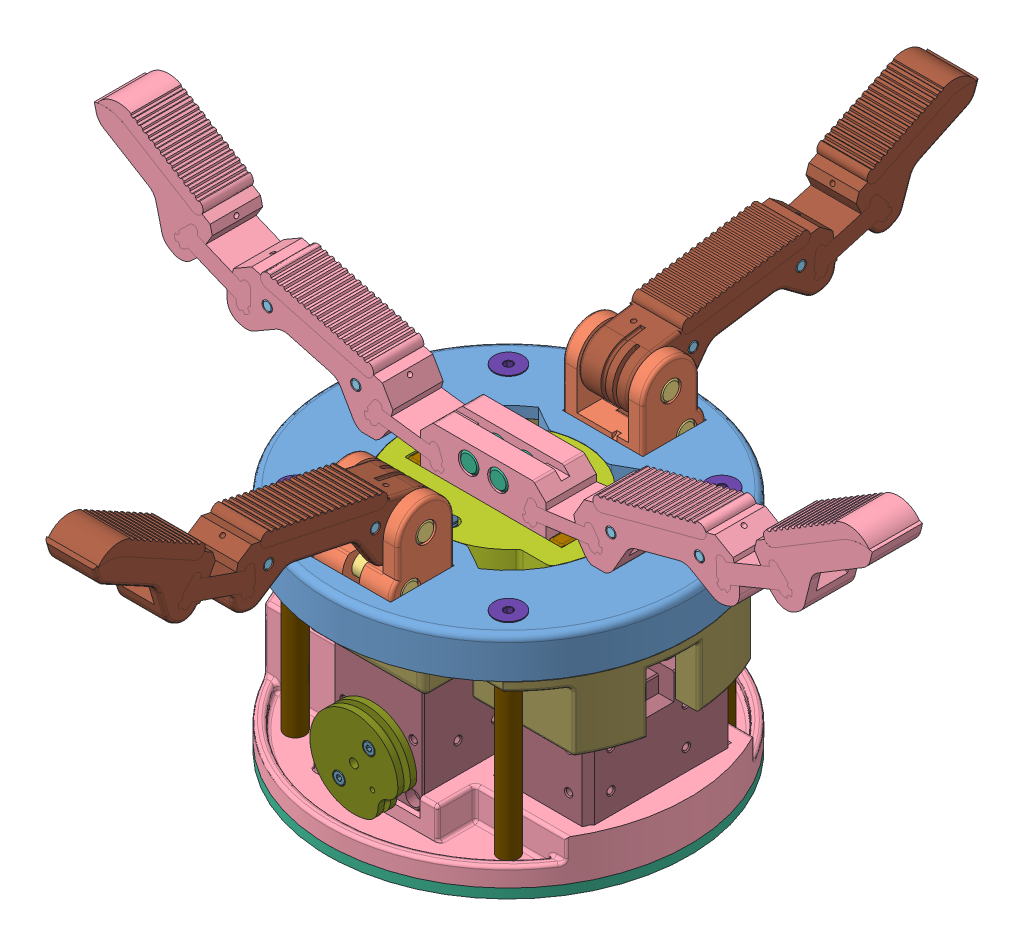
SolidWorks assembly hand_q, configuration Default. Lengths in mm.
Overall size (247.99 129.84 290.7).
63 component instances, 24 part files, 66 mates.
Components (placement in the parent):
- asm_upper_hand-1: asm_upper_hand [Default] at (50.9892 100.6769 120.1073) size (247.99 72.36 290.7)
  - top_outer-1: top_outer [Default] at (34.5547 64.3421 89.7406) size (115 12.78 115)
  - finger_base_pf-1: finger_base_pf [Default] at (4.6376 22.7271 -88.248) size (33.5 28.98 20.18)
    - pivot_base-1: pivot_base [Default] at (29.9046 41.615 134.046) x (-1 0 0) z (0 0 -1) size (33.5 28.98 20.18)
    - 98381A542 D1-4 L1-1: 98381A542 D1-4 L1 [98381A542] at (29.9546 61.59 138.9886) size (25.4 6.35 6.35)
    - 98381A542 D1-4 L1-2: 98381A542 D1-4 L1 [98381A542] at (29.9546 47.8525 134.046) size (25.4 6.35 6.35)
  - finger_base_pf-2: finger_base_pf [Default] at (64.4468 22.7271 267.7291) x (-1 0 0) z (0 0 -1) size (33.5 28.98 20.18)
    - pivot_base-1: pivot_base [Default] at (29.9046 41.615 134.046) x (-1 0 0) z (0 0 -1) size (33.5 28.98 20.18)
    - 98381A542 D1-4 L1-1: 98381A542 D1-4 L1 [98381A542] at (29.9546 61.59 138.9886) size (25.4 6.35 6.35)
    - 98381A542 D1-4 L1-2: 98381A542 D1-4 L1 [98381A542] at (29.9546 47.8525 134.046) size (25.4 6.35 6.35)
  - q_ffff-1: q_ffff [Default] at (44.5547 76.3421 89.7516) x (-0.001108 0 0.999999) z (-0.999999 0 -0.001108) size (24 58.4 247.96)
  - 98381A472 D1-8 L5-8-1: 98381A472 D1-8 L5-8 [98381A472] at (75.1996 82.7614 89.8481) x (-0.001108 0 0.999999) z (-0.999999 0 -0.001108) size (15.88 3.17 3.17)
  - 98381A539 D1-4 L5-8-1: 98381A539 D1-4 L5-8 [98381A539] at (29.8796 79.1671 89.7979) x (-0.001108 0 0.999999) z (-0.999999 0 -0.001108) size (15.88 6.35 6.35)
  - 98381A472 D1-8 L5-8-2: 98381A472 D1-8 L5-8 [98381A472] at (-34.3036 90.3211 89.7268) x (-0.001108 0 0.999999) z (-0.999999 0 -0.001108) size (15.88 3.17 3.17)
  - 98381A472 D1-8 L5-8-3: 98381A472 D1-8 L5-8 [98381A472] at (-6.0903 82.7614 89.758) x (-0.001108 0 0.999999) z (-0.999999 0 -0.001108) size (15.88 3.17 3.17)
  - 98381A472 D1-8 L5-8-4: 98381A472 D1-8 L5-8 [98381A472] at (103.4129 90.3211 89.8793) x (-0.001108 0 0.999999) z (-0.999999 0 -0.001108) size (15.88 3.17 3.17)
  - 98381A539 D1-4 L5-8-2: 98381A539 D1-4 L5-8 [98381A539] at (39.2296 79.1671 89.8082) x (-0.001108 0 0.999999) z (-0.999999 0 -0.001108) size (15.88 6.35 6.35)
  - top_inner-1: top_inner [Default] at (34.5547 64.3421 89.7406) x (0.999999 0 0.001108) z (-0.001108 0 0.999999) size (72 6.4 48)
  - 93365A130 6-32 insert-1: 93365A130 6-32 insert [Default] at (34.5752 68.1521 71.2406) x (1 0 0) z (0 -1 0) size (5.23 5.23 3.81)
  - 93365A130 6-32 insert-2: 93365A130 6-32 insert [Default] at (34.5342 68.1521 108.2406) x (1 0 0) z (0 -1 0) size (5.23 5.23 3.81)
  - gear_main-1: gear_main [Default] at (34.5547 61.0921 89.7406) x (-0.999999 0 -0.001108) z (0 -1 0) size (59.97 59.97 15.65)
  - 92196A146 6-32 L3-8  socket-1: 92196A146 6-32 L3-8  socket [Default] at (34.5342 58.3421 108.2406) x (1 0 0) z (0 1 0) size (5.74 5.74 13.34)
  - 92196A146 6-32 L3-8  socket-3: 92196A146 6-32 L3-8  socket [Default] at (34.5752 58.3421 71.2406) x (1 0 0) z (0 1 0) size (5.74 5.74 13.34)
  - q_pf-1: q_pf [Default] at (34.6922 84.3171 50.7406) x (1 0 0) z (0 -0.14871 0.988881) size (16.19 30.86 115.48)
  - 98381A472 D1-8 L5-8-5: 98381A472 D1-8 L5-8 [98381A472] at (34.7547 88.2661 39.0225) size (15.88 3.17 3.17)
  - 98381A472 D1-8 L5-8-6: 98381A472 D1-8 L5-8 [98381A472] at (34.7547 93.4305 4.6806) size (15.88 3.17 3.17)
  - 98381A472 D1-8 L5-8-7: 98381A472 D1-8 L5-8 [98381A472] at (34.6297 96.0106 174.214) x (-1 0 0) z (0 0 -1) size (15.88 3.17 3.17)
  - q_pf-2: q_pf [Default] at (34.6922 84.3171 128.7406) x (-1 0 0) z (0 -0.204177 -0.978934) size (16.19 30.86 115.48)
  - 98381A472 D1-8 L5-8-8: 98381A472 D1-8 L5-8 [98381A472] at (34.6297 88.9199 140.2176) x (-1 0 0) z (0 0 -1) size (15.88 3.17 3.17)
- mid_clamp-1: mid_clamp [Default] at (85.5439 155.519 209.8478) size (115 28.59 91.05)
- dynamixel XM-430-1: dynamixel XM-430 [Default] at (47.6198 138.519 196.7478) x (1 0 0) z (0 1 0) size (28.5 46.5 37.88)
- 91290A012 M2 L5 socket-1: 91290A012 M2 L5 socket [91290A012] at (53.2767 156.3984 202.4047) x (1 0 0) z (0 -1 0) size (3.8 3.8 7.09)
- gear_motor-1: gear_motor [Default] at (46.9298 161.9484 197.5346) x (1 0 0) z (0 1 0) size (27.89 27.89 7.3)
- dynamixel XM-430-2: dynamixel XM-430 [Default] at (85.7439 120.269 234.3728) x (-1 0 0) z (0 0 1) size (28.5 46.5 37.88)
- dynamixel XM-430-3: dynamixel XM-430 [Default] at (85.7439 120.269 185.3228) x (1 0 0) z (0 0 -1) size (28.5 46.5 37.88)
- dynamixel XM-430-4: dynamixel XM-430 [Default] at (121.2351 127.519 199.1567) x (-1 0 0) z (0 -1 0) size (28.5 46.5 37.88)
- horn2-1: horn2 [Default] at (85.7439 120.269 256.2522) x (0.804523 -0.593922 0) z (0 0 1) size (26.25 28 6)
- horn2-2: horn2 [Default] at (85.7439 120.269 163.4435) x (-0.894152 -0.447763 0) z (0 0 -1) size (26.25 28 6)
- 91290A012 M2 L5 socket-2: 91290A012 M2 L5 socket [91290A012] at (90.4953 126.7052 252.2522) x (-1 0 0) z (0 0 -1) size (3.8 3.8 7.09)
- 91290A012 M2 L5 socket-3: 91290A012 M2 L5 socket [91290A012] at (80.9926 113.8328 252.2522) x (-1 0 0) z (0 0 -1) size (3.8 3.8 7.09)
- 91290A012 M2 L5 socket-4: 91290A012 M2 L5 socket [91290A012] at (89.326 113.1158 167.4435) size (3.8 3.8 7.09)
- 91290A012 M2 L5 socket-5: 91290A012 M2 L5 socket [91290A012] at (82.1618 127.4222 167.4435) x (-0.05549 0.998459 0) z (0 0 1) size (3.8 3.8 7.09)
- 92210A197 8-32 L3-4 countersunk-1: 92210A197 8-32 L3-4 countersunk [92210A197] at (119.4851 171.7035 243.789) x (1 0 0) z (0 1 0) size (9.12 9.12 19.5)
- 92210A197 8-32 L3-4 countersunk-2: 92210A197 8-32 L3-4 countersunk [92210A197] at (119.4851 171.7035 175.9067) x (1 0 0) z (0 1 0) size (9.12 9.12 19.5)
- 92210A197 8-32 L3-4 countersunk-3: 92210A197 8-32 L3-4 countersunk [92210A197] at (51.6028 171.7035 175.9067) x (1 0 0) z (0 1 0) size (9.12 9.12 19.5)
- 92210A197 8-32 L3-4 countersunk-4: 92210A197 8-32 L3-4 countersunk [92210A197] at (51.6028 171.7035 243.789) x (1 0 0) z (0 1 0) size (9.12 9.12 19.5)
- 93330A483 8-32 L2 standoff-1: 93330A483 8-32 L2 standoff [93330A483] at (119.4851 130.119 175.9067) x (1 0 0) z (0 1 0) size (6.35 6.35 51.89)
- 93330A483 8-32 L2 standoff-2: 93330A483 8-32 L2 standoff [93330A483] at (119.4851 130.119 243.789) x (1 0 0) z (0 1 0) size (6.35 6.35 51.89)
- 93330A483 8-32 L2 standoff-3: 93330A483 8-32 L2 standoff [93330A483] at (51.6028 130.119 243.789) x (1 0 0) z (0 -1 0) size (6.35 6.35 51.89)
- 93330A483 8-32 L2 standoff-4: 93330A483 8-32 L2 standoff [93330A483] at (51.6028 130.119 175.9067) x (1 0 0) z (0 1 0) size (6.35 6.35 51.89)
- 3434T31 - nylon pulley-1: 3434T31 - nylon pulley [Default] at (85.4871 147.8053 209.6723) x (0.003297 0.136497 0.990635) z (-0.087526 -0.986799 0.13626) size (9.5 2.4 9.5)
- pulley_block_half-1: pulley_block_half [Default] at (81.8013 148.1278 209.6401) x (0.008727 0 -0.999962) z (0.996157 -0.087156 0.008693) size (10 17 3.85)
- pulley_block_half-2: pulley_block_half [Default] at (89.1728 147.4828 209.7045) x (-0.008727 0 0.999962) z (-0.996157 0.087156 -0.008693) size (10 17 3.85)
- 97395A435 D1-8 L3-8-1: 97395A435 D1-8 L3-8 [97395A435] at (85.0538 139.8127 209.6685) x (-0.996157 0.087156 -0.008693) z (-0.010913 -0.221983 -0.974989) size (9.53 3.17 3.17)
- bottom_no_bridge-1: bottom_no_bridge [Default] at (85.5439 101.719 209.8478) size (115 26.28 115)
- bottom_reroute-1: bottom_reroute [Default] at (87.1314 109.3065 209.7853) size (17.18 15.18 9.75)
- 97395A435 D1-8 L3-8-2: 97395A435 D1-8 L3-8 [97395A435] at (87.1314 109.3065 209.6728) x (0 0 1) z (-1 0 0) size (9.53 3.17 3.17)
- bottom_brace_insertv2-1: bottom_brace_insertv2 [Default] at (85.5439 98.719 209.8478) size (115 3 115)
- 92210A197 8-32 L3-4 countersunk-5: 92210A197 8-32 L3-4 countersunk [92210A197] at (51.6028 98.4345 175.9067) x (1 0 0) z (0 -1 0) size (9.12 9.12 19.5)
- 92210A197 8-32 L3-4 countersunk-6: 92210A197 8-32 L3-4 countersunk [92210A197] at (51.6028 98.4345 243.789) x (1 0 0) z (0 -1 0) size (9.12 9.12 19.5)
- 92210A197 8-32 L3-4 countersunk-7: 92210A197 8-32 L3-4 countersunk [92210A197] at (119.4851 98.4345 175.9067) x (0.957258 0 -0.289237) z (0 -1 0) size (9.12 9.12 19.5)
- 92210A197 8-32 L3-4 countersunk-8: 92210A197 8-32 L3-4 countersunk [92210A197] at (119.4851 98.4345 243.789) x (1 0 0) z (0 -1 0) size (9.12 9.12 19.5)
- 97395A435 D1-8 L3-8-3: 97395A435 D1-8 L3-8 [97395A435] at (84.7449 147.8702 209.6658) x (0.996157 -0.087156 0.008693) z (-0.016224 -0.086073 0.996157) size (9.53 3.17 3.17)
Mates (geometry in assembly coordinates):
- Coincident1: coincident: plane of mid_clamp-1 through (47.8198 155.519 196.5478) normal (0 -1 0); plane of dynamixel XM-430-1 through (47.6198 155.519 196.7478) normal (0 1 0)
- Coincident2: coincident: plane of mid_clamp-1 through (33.3698 145.519 209.8478) normal (1 0 0); plane of dynamixel XM-430-1 through (33.3698 121.519 185.4978) normal (-1 0 0)
- Coincident3: coincident: plane of mid_clamp-1 through (85.5439 145.519 231.9978) normal (0 0 -1); plane of dynamixel XM-430-1 through (33.3698 121.519 231.9978) normal (0 0 1)
- Coincident4: coincident: plane of dynamixel XM-430-1 through (47.6198 159.3984 196.7478) normal (0 1 0); plane of gear_motor-1 through (46.9298 159.3984 197.5346) normal (0 -1 0)
- Concentric1: concentric: circle of dynamixel XM-430-1; circle of gear_motor-1
- Coincident14: coincident: plane of 91290A012 M2 L5 socket-1 through (53.2767 161.3984 202.4047) normal (0 -1 0); plane of gear_motor-1 through (53.2767 161.3984 202.4047) normal (0 1 0)
- Concentric2: concentric: circle of 91290A012 M2 L5 socket-1; circle of gear_motor-1
- Concentric3: concentric: circle of asm_upper_hand-1/top_outer-1; circle of mid_clamp-1
- Concentric4: concentric: cylinder of asm_upper_hand-1/top_outer-1 through (51.6028 171.419 243.789) axis (0 1 0) radius 2.4574; circle of mid_clamp-1
- Coincident16: coincident: plane of asm_upper_hand-1/top_outer-1 through (85.5439 165.019 209.8478) normal (0 -1 0); plane of mid_clamp-1 through (85.5439 165.019 209.8478) normal (0 1 0)
- Coincident17: coincident: plane of mid_clamp-1 through (47.8198 155.519 196.5478) normal (0 -1 0); plane of dynamixel XM-430-2 through (99.9939 155.519 217.3728) normal (0 1 0)
- Coincident18: coincident: plane of mid_clamp-1 through (99.9939 145.519 209.8478) normal (-1 0 0); plane of dynamixel XM-430-2 through (99.9939 109.019 217.3728) normal (1 0 0)
- Coincident19: coincident: plane of mid_clamp-1 through (85.5439 155.519 251.3728) normal (0 0 -1); plane of dynamixel XM-430-2 through (85.7439 120.269 251.3728) normal (0 0 1)
- Coincident20: coincident: plane of mid_clamp-1 through (85.5439 155.519 168.3228) normal (0 0 1); plane of dynamixel XM-430-3 through (85.7439 120.269 168.3228) normal (0 0 -1)
- Coincident21: coincident: plane of mid_clamp-1 through (99.9939 145.519 209.8478) normal (-1 0 0); plane of dynamixel XM-430-3 through (99.9939 155.519 202.3228) normal (1 0 0)
- Coincident22: coincident: plane of mid_clamp-1 through (47.8198 155.519 196.5478) normal (0 -1 0); plane of dynamixel XM-430-3 through (71.4939 155.519 202.3228) normal (0 1 0)
- Coincident25: coincident: plane of dynamixel XM-430-2 through (85.7439 120.269 255.2522) normal (0 0 1); plane of horn2-1 through (85.7439 120.269 255.2522) normal (0 0 -1)
- Concentric6: concentric: circle of dynamixel XM-430-2; circle of horn2-1
- Coincident28: coincident: plane of dynamixel XM-430-3 through (85.7439 120.269 164.4435) normal (0 0 -1); plane of horn2-2 through (85.7439 120.269 164.4435) normal (0 0 1)
- Concentric8: concentric: cylinder of dynamixel XM-430-3 through (85.7439 120.269 168.3228) axis (0 0 -1) radius 4; cylinder of horn2-2 through (85.7439 120.269 160.4435) axis (0 0 1) radius 4.175
- Coincident34: coincident: cone of asm_upper_hand-1/top_outer-1 through (119.4851 171.419 243.789) axis (0 -1 0); cone of 92210A197 8-32 L3-4 countersunk-1 through (119.4851 168.8587 243.789) axis (0 -1 0)
- Coincident35: coincident: cone of asm_upper_hand-1/top_outer-1 through (51.6028 171.419 243.789) axis (0 -1 0); cone of 92210A197 8-32 L3-4 countersunk-4 through (51.6028 168.8587 243.789) axis (0 -1 0)
- Coincident36: coincident: cone of asm_upper_hand-1/top_outer-1 through (51.6028 171.419 175.9067) axis (0 -1 0); cone of 92210A197 8-32 L3-4 countersunk-3 through (51.6028 168.8587 175.9067) axis (0 -1 0)
- Coincident37: coincident: cone of asm_upper_hand-1/top_outer-1 through (119.4851 171.419 175.9067) axis (0 -1 0); cone of 92210A197 8-32 L3-4 countersunk-2 through (119.4851 168.8587 175.9067) axis (0 -1 0)
- Concentric14: concentric: circle of mid_clamp-1; circle of 93330A483 8-32 L2 standoff-1
- Coincident38: coincident: plane of mid_clamp-1 through (47.8198 155.519 196.5478) normal (0 -1 0); plane of 93330A483 8-32 L2 standoff-1 through (119.4851 155.519 175.9067) normal (0 1 0)
- Concentric15: concentric: circle of mid_clamp-1; circle of 93330A483 8-32 L2 standoff-4
- Coincident39: coincident: plane of mid_clamp-1 through (47.8198 155.519 196.5478) normal (0 -1 0); plane of 93330A483 8-32 L2 standoff-4 through (51.6028 155.519 175.9067) normal (0 1 0)
- Coincident40: coincident: plane of mid_clamp-1 through (47.8198 155.519 196.5478) normal (0 -1 0); plane of 93330A483 8-32 L2 standoff-3 through (51.6028 155.519 243.789) normal (0 1 0)
- Concentric16: concentric: circle of mid_clamp-1; circle of 93330A483 8-32 L2 standoff-3
- Concentric17: concentric: circle of mid_clamp-1; circle of 93330A483 8-32 L2 standoff-2
- Coincident41: coincident: plane of mid_clamp-1 through (47.8198 155.519 196.5478) normal (0 -1 0); plane of 93330A483 8-32 L2 standoff-2 through (119.4851 155.519 243.789) normal (0 1 0)
- Coincident42: coincident: plane of mid_clamp-1 through (85.5439 144.519 209.8478) normal (0 -1 0); plane of dynamixel XM-430-4 through (121.2351 144.519 199.1567) normal (0 1 0)
- Coincident43: coincident: plane of mid_clamp-1 through (135.4851 145.519 209.8478) normal (-1 0 0); plane of dynamixel XM-430-4 through (135.4851 144.519 187.9067) normal (1 0 0)
- Coincident44: coincident: plane of mid_clamp-1 through (85.5439 145.519 187.9067) normal (0 0 1); plane of dynamixel XM-430-4 through (106.9851 144.519 187.9067) normal (0 0 -1)
- Coincident45: coincident: plane of 3434T31 - nylon pulley-1 through (84.2966 148.1146 211.1478) normal (-0.996157 0.087156 -0.008693); plane of pulley_block_half-1 through (84.2917 147.9099 209.6619) normal (0.996157 -0.087156 0.008693)
- Concentric18: concentric: circle of 3434T31 - nylon pulley-1; circle of pulley_block_half-1
- Coincident46: coincident: plane of 3434T31 - nylon pulley-1 through (86.6874 147.9055 211.1687) normal (0.996157 -0.087156 0.008693); plane of pulley_block_half-2 through (86.6824 147.7007 209.6827) normal (-0.996157 0.087156 -0.008693)
- Concentric19: concentric: circle of 3434T31 - nylon pulley-1; circle of pulley_block_half-2
- Concentric20: concentric: circle of pulley_block_half-2; circle of 97395A435 D1-8 L3-8-1
- Concentric21: concentric: circle of pulley_block_half-2; circle of 97395A435 D1-8 L3-8-1
- Concentric22: concentric: circle of pulley_block_half-1; circle of 97395A435 D1-8 L3-8-1
- Concentric25: concentric: cylinder of 93330A483 8-32 L2 standoff-2 through (119.4851 155.519 243.789) axis (0 -1 0) radius 3.175; circle of bottom_no_bridge-1
- Concentric26: concentric: cylinder of 93330A483 8-32 L2 standoff-1 through (119.4851 155.519 175.9067) axis (0 -1 0) radius 3.175; circle of bottom_no_bridge-1
- Coincident56: coincident: plane of bottom_no_bridge-1 through (82.5439 101.719 204.9103) normal (0 0 1); plane of bottom_reroute-1 through (87.1314 109.3065 204.9103) normal (0 0 -1)
- Coincident57: coincident: plane of bottom_no_bridge-1 through (82.5439 101.719 204.9103) normal (1 0 0); plane of bottom_reroute-1 through (82.5439 109.3065 214.6603) normal (-1 0 0)
- Concentric27: concentric: cylinder of bottom_reroute-1 through (87.1314 109.3065 214.6603) axis (0 0 -1) radius 1.6375; cylinder of 97395A435 D1-8 L3-8-2 through (87.1314 109.3065 204.9103) axis (0 0 1) radius 1.5875
- Coincident58: coincident: plane of bottom_reroute-1 through (87.1314 109.3065 204.9103) normal (0 0 -1); plane of 97395A435 D1-8 L3-8-2 through (87.1314 109.3065 204.9103) normal (0 0 -1)
- Coincident59: coincident: plane of bottom_no_bridge-1 through (85.5439 101.719 209.8478) normal (0 -1 0); plane of bottom_reroute-1 through (91.7189 101.719 214.6603) normal (0 1 0)
- Coincident60: coincident: circle of 93330A483 8-32 L2 standoff-1; plane of bottom_no_bridge-1 through (85.5439 104.719 209.8478) normal (0 1 0)
- Coincident61: coincident: plane of bottom_no_bridge-1 through (85.5439 101.719 209.8478) normal (0 -1 0); plane of bottom_brace_insertv2-1 through (85.5439 101.719 209.8478) normal (0 1 0)
- Concentric28: concentric: circle of 93330A483 8-32 L2 standoff-3; circle of bottom_brace_insertv2-1
- Concentric30: concentric: circle of bottom_no_bridge-1; circle of bottom_brace_insertv2-1
- Coincident62: coincident: circle of bottom_brace_insertv2-1; cone of 92210A197 8-32 L3-4 countersunk-6 through (51.6028 101.2793 243.789) axis (0 1 0)
- Coincident63: coincident: cone of bottom_brace_insertv2-1 through (119.4851 98.719 243.789) axis (0 1 0); cone of 92210A197 8-32 L3-4 countersunk-8 through (119.4851 101.2793 243.789) axis (0 1 0)
- Coincident64: coincident: cone of bottom_brace_insertv2-1 through (51.6028 98.719 175.9067) axis (0 1 0); cone of 92210A197 8-32 L3-4 countersunk-5 through (51.6028 101.2793 175.9067) axis (0 1 0)
- Coincident65: coincident: circle of bottom_brace_insertv2-1; cone of 92210A197 8-32 L3-4 countersunk-7 through (119.4851 101.2793 175.9067) axis (0 1 0)
- Coincident67: coincident: circle of pulley_block_half-2; circle of 97395A435 D1-8 L3-8-3
- Coincident68: coincident: plane of horn2-1 through (85.7439 120.269 257.2522) normal (0 0 1); plane of 91290A012 M2 L5 socket-3 through (80.9926 113.8328 257.2522) normal (0 0 -1)
- Concentric31: concentric: circle of horn2-1; circle of 91290A012 M2 L5 socket-3
- Coincident69: coincident: plane of horn2-1 through (85.7439 120.269 257.2522) normal (0 0 1); plane of 91290A012 M2 L5 socket-2 through (90.4953 126.7052 257.2522) normal (0 0 -1)
- Concentric32: concentric: circle of horn2-1; circle of 91290A012 M2 L5 socket-2
- Concentric33: concentric: circle of horn2-2; circle of 91290A012 M2 L5 socket-5
- Coincident71: coincident: plane of horn2-2 through (85.7439 120.269 162.4435) normal (0 0 -1); plane of 91290A012 M2 L5 socket-5 through (82.1618 127.4222 162.4435) normal (0 0 1)
- Coincident72: coincident: plane of horn2-2 through (85.7439 120.269 162.4435) normal (0 0 -1); plane of 91290A012 M2 L5 socket-4 through (89.326 113.1158 162.4435) normal (0 0 1)
- Concentric34: concentric: circle of horn2-2; circle of 91290A012 M2 L5 socket-4
